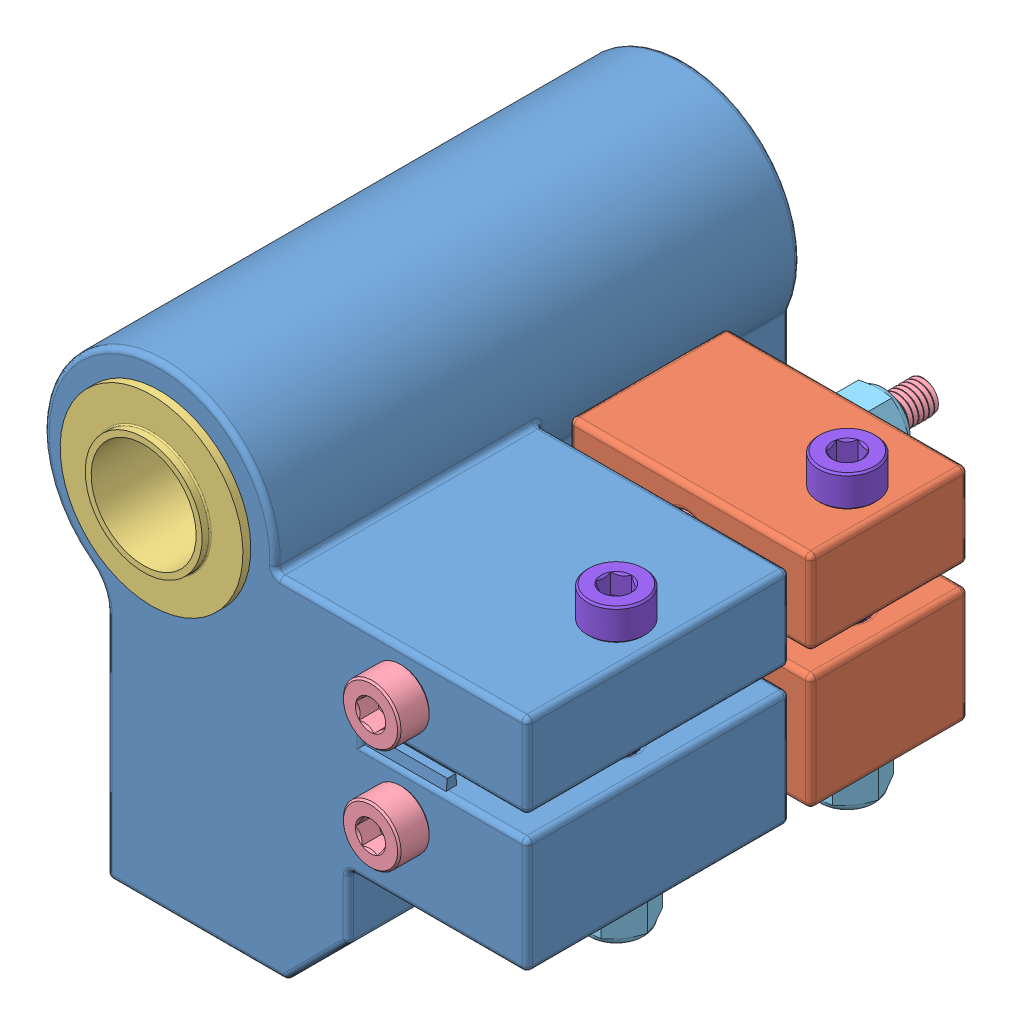
SolidWorks assembly XY_Axis_Belt_Tensioner_A, configuration Default. Lengths in mm.
Overall size (46.05 45 54.64).
14 component instances, 8 part files, 28 mates.
Components (placement in the parent):
- XY Axis Belt Tensioner A-1: XY Axis Belt Tensioner A [Default] at origin size (46 45 50)
- XY Axis Belt Tensioner Block A-1: XY Axis Belt Tensioner Block A [Default] at (0 1 -9.5) size (23 21 15.06)
- a_7z41mpsb10m-1: a_7z41mpsb10m [Default] at (5 34 25.75) x (1 0 0) z (0 1 0) size (17.4 11.55 17.4)
- a_7z41mpsb10m-2: a_7z41mpsb10m [Default] at (5 34 -25.75) x (1 0 0) z (0 -1 0) size (17.4 11.55 17.4)
- 3mmX50mm_Sockethead(McMaster_91290A137)-1: 3mmX50mm_Sockethead(McMaster_91290A137) [91290A137] at (28.1 29 -25) x (-0.305644 -0.952146 0) z (0 0 -1) size (5.5 5.5 53.26)
- 3mmX50mm_Sockethead(McMaster_91290A137)-2: 3mmX50mm_Sockethead(McMaster_91290A137) [91290A137] at (28.1 19 -25) x (-0.07329 -0.997311 0) z (0 0 -1) size (5.5 5.5 53.26)
- 3mm_Hex_Nylock_Nut(McMaster_90576A102)-1: 3mm_Hex_Nylock_Nut(McMaster_90576A102) [90576A102] at (28.1 29 -17) x (-0.882745 0.469853 0) z (-0.469853 -0.882745 0) size (5.5 4.1 6.35)
- 3mm_Hex_Nylock_Nut(McMaster_90576A102)-2: 3mm_Hex_Nylock_Nut(McMaster_90576A102) [90576A102] at (28.1 19 -17) x (0.115123 -0.993351 0) z (0.993351 0.115123 0) size (5.5 4.1 6.35)
- 5mm_Hex_Nut(McMaster_90591A146)-1: 5mm_Hex_Nut(McMaster_90591A146) [90591A146] at (7.5 21.375 -16.6) x (0.5 0 0.866025) z (-0.866025 0 0.5) size (8 4.31 9.24)
- 5mmX16mm_Buttonhead(McMaster_91239A232)-1: 5mmX16mm_Buttonhead(McMaster_91239A232) [91239A232] at (7.5 3.25 -16.6) x (0.988862 0 -0.148837) z (0 -1 0) size (9.5 9.5 19.24)
- 3mmX25mm_Sockethead(McMaster_91290A125)-1: 3mmX25mm_Sockethead(McMaster_91290A125) [91290A125] at (36 8 -9.5) x (0.717938 0 0.696107) z (0 -1 0) size (5.5 5.5 28.26)
- 3mmX25mm_Sockethead(McMaster_91290A125)-2: 3mmX25mm_Sockethead(McMaster_91290A125) [91290A125] at (36 8 12.5) x (1 0 0.00085) z (0 -1 0) size (5.5 5.5 28.26)
- 3mm_Hex_Nylock_Nut(McMaster_90576A102)-3: 3mm_Hex_Nylock_Nut(McMaster_90576A102) [90576A102] at (36 12 12.5) x (-0.832486 0 -0.554046) z (-0.554046 0 0.832486) size (5.5 4.1 6.35)
- 3mm_Hex_Nylock_Nut(McMaster_90576A102)-4: 3mm_Hex_Nylock_Nut(McMaster_90576A102) [90576A102] at (36 12 -9.5) x (-0.836182 0 -0.548452) z (-0.548452 0 0.836182) size (5.5 4.1 6.35)
Mates (geometry in assembly coordinates):
- Concentric1: concentric aligned: cylinder of XY Axis Belt Tensioner A-1 through (5 34 14) axis (0 0 1) radius 7.95; circle of a_7z41mpsb10m-1
- Coincident1: coincident anti-aligned: plane of XY Axis Belt Tensioner A-1 through (-4 22 25) normal (0 0 1); plane of a_7z41mpsb10m-1 through (5 34 25) normal (0 0 -1)
- Concentric2: concentric aligned: cylinder of XY Axis Belt Tensioner A-1 through (5 34 -14) axis (0 0 -1) radius 7.95; circle of a_7z41mpsb10m-2
- Coincident2: coincident anti-aligned: plane of XY Axis Belt Tensioner A-1 through (-4 22 -25) normal (0 0 -1); plane of a_7z41mpsb10m-2 through (5 34 -25) normal (0 0 1)
- Concentric322: concentric aligned: cylinder of XY Axis Belt Tensioner A-1 through (28.1 29 25) axis (0 0 -1) radius 1.6; cylinder of XY Axis Belt Tensioner Block A-1 through (28.1 29 -2) axis (0 0 -1) radius 1.6
- Concentric323: concentric aligned: cylinder of XY Axis Belt Tensioner A-1 through (28.1 19 25) axis (0 0 -1) radius 1.6; cylinder of XY Axis Belt Tensioner Block A-1 through (28.1 19 -2) axis (0 0 -1) radius 1.6
- Distance1: distance = 2 mm anti-aligned: plane of XY Axis Belt Tensioner A-1 through (0 0 0) normal (0 0 -1); plane of XY Axis Belt Tensioner Block A-1 through (0 1 -2) normal (0 0 1)
- Parallel1: parallel aligned: plane of 5mm_Hex_Nut(McMaster_90591A146)-1 through (11.5 23.375 -14.2906) normal (1 0 0); plane of XY Axis Belt Tensioner A-1 through (3.375 19.375 -10.1) normal (1 0 0)
- Concentric324: concentric aligned: cylinder of XY Axis Belt Tensioner A-1 through (7.5 25 -16.6) axis (0 -1 0) radius 2.6; circle of 5mm_Hex_Nut(McMaster_90591A146)-1
- Coincident4: coincident anti-aligned: plane of XY Axis Belt Tensioner A-1 through (11.625 19.375 -10.1) normal (0 1 0); plane of 5mm_Hex_Nut(McMaster_90591A146)-1 through (11.5 19.375 -23.5282) normal (0 -1 0)
- Concentric325: concentric aligned: cylinder of XY Axis Belt Tensioner A-1 through (7.5 25 -16.6) axis (0 -1 0) radius 2.6; cylinder of 5mmX16mm_Buttonhead(McMaster_91239A232)-1 through (7.5 3.25 -16.6) axis (0 -1 0) radius 4.75
- Coincident5: coincident anti-aligned: plane of XY Axis Belt Tensioner A-1 through (7.5 6 -16.6) normal (0 -1 0); plane of 5mmX16mm_Buttonhead(McMaster_91239A232)-1 through (6.793 6 -21.2971) normal (0 1 0)
- Concentric326: concentric aligned: cylinder of XY Axis Belt Tensioner Block A-1 through (28.1 19 -2) axis (0 0 -1) radius 1.6; cylinder of 3mmX50mm_Sockethead(McMaster_91290A137)-2 through (28.1 19 25) axis (0 0 -1) radius 1.5
- Concentric327: concentric aligned: cylinder of XY Axis Belt Tensioner Block A-1 through (28.1 29 -2) axis (0 0 -1) radius 1.6; cylinder of 3mmX50mm_Sockethead(McMaster_91290A137)-1 through (28.1 29 25) axis (0 0 -1) radius 1.5
- Coincident6: coincident anti-aligned: plane of XY Axis Belt Tensioner A-1 through (-4 22 25) normal (0 0 1); plane of 3mmX50mm_Sockethead(McMaster_91290A137)-1 through (28.1 29 25) normal (0 0 -1)
- Coincident7: coincident anti-aligned: plane of XY Axis Belt Tensioner A-1 through (-4 22 25) normal (0 0 1); plane of 3mmX50mm_Sockethead(McMaster_91290A137)-2 through (28.1 19 25) normal (0 0 -1)
- Concentric328: concentric anti-aligned: cylinder of 3mmX50mm_Sockethead(McMaster_91290A137)-1 through (28.1 29 25) axis (0 0 -1) radius 1.5; cylinder of 3mm_Hex_Nylock_Nut(McMaster_90576A102)-1 through (28.1 29 -20.4095) axis (0 0 1) radius 1.269
- Coincident9: coincident anti-aligned: plane of XY Axis Belt Tensioner Block A-1 through (0 1 -17) normal (0 0 -1); plane of 3mm_Hex_Nylock_Nut(McMaster_90576A102)-1 through (29.592 31.8031 -17) normal (0 0 1)
- Concentric330: concentric anti-aligned: cylinder of 3mmX50mm_Sockethead(McMaster_91290A137)-2 through (28.1 19 25) axis (0 0 -1) radius 1.5; cylinder of 3mm_Hex_Nylock_Nut(McMaster_90576A102)-2 through (28.1 19 -20.4095) axis (0 0 1) radius 1.269
- Coincident10: coincident anti-aligned: plane of XY Axis Belt Tensioner Block A-1 through (0 1 -17) normal (0 0 -1); plane of 3mm_Hex_Nylock_Nut(McMaster_90576A102)-2 through (24.9457 18.6344 -17) normal (0 0 1)
- Concentric331: concentric anti-aligned: cylinder of XY Axis Belt Tensioner A-1 through (36 7.4745 12.5) axis (0 1 0) radius 1.6; cylinder of 3mmX25mm_Sockethead(McMaster_91290A125)-2 through (36 33 12.5) axis (0 -1 0) radius 1.5
- Concentric332: concentric anti-aligned: cylinder of XY Axis Belt Tensioner Block A-1 through (36 7.4745 -9.5) axis (0 1 0) radius 1.6; cylinder of 3mmX25mm_Sockethead(McMaster_91290A125)-1 through (36 33 -9.5) axis (0 -1 0) radius 1.5
- Coincident11: coincident anti-aligned: plane of XY Axis Belt Tensioner A-1 through (40 33 25) normal (0 1 0); plane of 3mmX25mm_Sockethead(McMaster_91290A125)-2 through (36 33 12.5) normal (0 -1 0)
- Coincident12: coincident anti-aligned: plane of XY Axis Belt Tensioner Block A-1 through (40 33 -2) normal (0 1 0); plane of 3mmX25mm_Sockethead(McMaster_91290A125)-1 through (36 33 -9.5) normal (0 -1 0)
- Concentric333: concentric aligned: cylinder of XY Axis Belt Tensioner A-1 through (36 7.4745 12.5) axis (0 1 0) radius 1.6; cylinder of 3mm_Hex_Nylock_Nut(McMaster_90576A102)-3 through (36 8.5905 12.5) axis (0 1 0) radius 1.269
- Concentric334: concentric aligned: cylinder of XY Axis Belt Tensioner Block A-1 through (36 7.4745 -9.5) axis (0 1 0) radius 1.6; cylinder of 3mm_Hex_Nylock_Nut(McMaster_90576A102)-4 through (36 8.5905 -9.5) axis (0 1 0) radius 1.269
- Coincident13: coincident anti-aligned: plane of XY Axis Belt Tensioner A-1 through (23 12 25) normal (0 -1 0); plane of 3mm_Hex_Nylock_Nut(McMaster_90576A102)-3 through (37.7593 12 9.8565) normal (0 1 0)
- Coincident14: coincident anti-aligned: plane of XY Axis Belt Tensioner Block A-1 through (17 12 -2) normal (0 -1 0); plane of 3mm_Hex_Nylock_Nut(McMaster_90576A102)-4 through (37.7416 12 -12.1552) normal (0 1 0)
